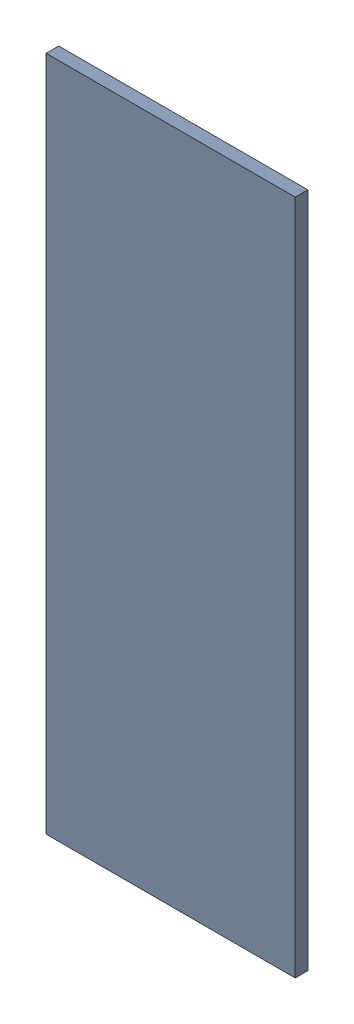
SolidWorks assembly Pad RAK4600-21(26.225mm,8.691mm) on Top Layer, configuration Predeterminado. Lengths in mm.
Overall size (0.7 1.9 0.04).
2 component instances, 1 part files, 0 mates.
Components (placement in the parent):
- Pad RAK4600-21(26.225mm,8.691mm) on Top Layer-1-1: Pad RAK4600-21(26.225mm,8.691mm) on Top Layer-1 [Predeterminado] at (-68.317 -44.187 -0.0457) size (0.7 1.9 0.04)
  - Pad RAK4600-21(26.225mm,8.691mm) on Top Layer-Part-1-1: Pad RAK4600-21(26.225mm,8.691mm) on Top Layer-Part-1 [Predeterminado] at origin size (0.7 1.9 0.04)
